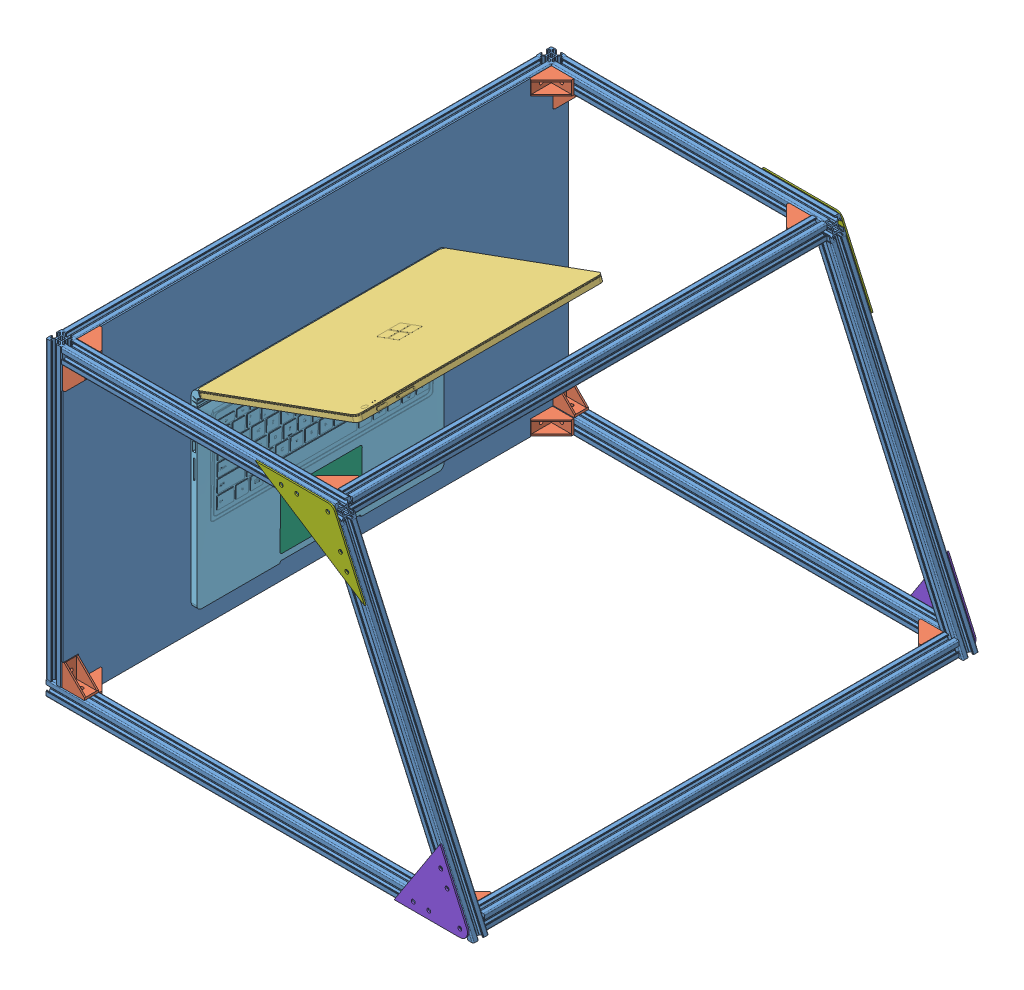
SolidWorks assembly LC, configuration Default. Lengths in mm.
Overall size (629.33 485.11 655).
26 component instances, 8 part files, 64 mates.
Components (placement in the parent):
- Laptop Area Chassis-1: Laptop Area Chassis [Default<As Machined>] at (20.6223 518.2446 805.6712) size (550.43 400 651)
- L- Bracket-1: L- Bracket [Default] at (21.1239 508.2457 184.6697) x (-1 0 0) z (0 1 0) size (18 29 29)
- L- Bracket-2: L- Bracket [Default] at (365.6239 517.7435 184.6697) x (0 -1 0) z (0 0 -1) size (18 29 29)
- L- Bracket-3: L- Bracket [Default] at (535.6239 138.7457 184.6697) x (0 1 0) z (1 0 0) size (18 29 29)
- L- Bracket-4: L- Bracket [Default] at (535.6239 138.7457 795.671) x (0 1 0) z (0 0 1) size (18 29 29)
- L- Bracket-5: L- Bracket [Default] at (365.6239 517.7435 795.671) x (0 1 0) z (0 0 1) size (18 29 29)
- L- Bracket-6: L- Bracket [Default] at (21.1239 508.2457 795.671) x (1 0 0) z (0 1 0) size (18 29 29)
- L- Bracket-7: L- Bracket [Default] at (21.1239 148.2435 795.671) size (18 29 29)
- L- Bracket-8: L- Bracket [Default] at (21.1234 148.2435 184.6697) x (-1 0 0) z (0 0 -1) size (18 29 29)
- L- Bracket-10: L- Bracket [Default] at (30.6226 518.7457 795.671) x (0 -1 0) z (0 0 1) size (18 29 29)
- L- Bracket-11: L- Bracket [Default] at (30.6212 508.2458 805.1697) x (0 0 1) z (0 1 0) size (18 29 29)
- L- Bracket-12: L- Bracket [Default] at (30.6212 148.2435 806.171) x (0 0 -1) z (0 -1 0) size (18 29 29)
- L- Bracket-13: L- Bracket [Default] at (30.6226 138.7457 795.671) x (0 -1 0) z (0 0 1) size (18 29 29)
- L- Bracket-14: L- Bracket [Default] at (30.6226 517.7435 184.6697) x (0 -1 0) z (-1 0 0) size (18 29 29)
- L- Bracket-15: L- Bracket [Default] at (30.6212 508.2458 174.1697) x (0 0 1) z (0 1 0) size (18 29 29)
- L- Bracket-16: L- Bracket [Default] at (30.6226 138.7457 184.6697) x (0 -1 0) z (-1 0 0) size (18 29 29)
- L- Bracket-17: L- Bracket [Default] at (30.6212 148.2435 175.171) x (0 0 -1) z (0 -1 0) size (18 29 29)
- Laptop-1: Laptop [Default] at (141.9009 439.4853 491.6697) x (0 0 -1) z (0.34202 -0.939693 0) size (328.58 310.16 232.04) (flexible)
  - Monitor-1: Monitor [Default] at origin size (318 220.5 8.05)
  - Display-1: Display [Default] at (0 0 7.5) size (326.85 238.53 0.46)
  - Main Body-1: Main Body [Default] at origin size (318.39 103.66 231.99)
  - Mouse Pad-1: Mouse Pad [Default] at (0 -91.311 -34.924) x (1 0 0) z (0 0.934014 0.357236) size (105 71 0.7)
- LC Lower Level-1: LC Lower Level [Default] at (97.0709 784.7388 817.6697) x (-0.543907 -0.839146 0) z (0.839146 -0.543907 0) size (52.47 2 167.83)
- LC Lower Level-2: LC Lower Level [Default] at (732.6289 372.7908 162.671) x (-0.543907 -0.839146 0) z (-0.839146 0.543907 0) size (52.47 2 167.83)
- LC Upper Level-1: LC Upper Level [Default] at (500.3977 162.4909 164.671) x (-0.839167 0.543874 0) z (-0.543874 -0.839167 0) size (75.53 2 108.78)
- LC Upper Level-2: LC Upper Level [Default] at (505.0206 169.6236 815.6697) x (-0.839167 0.543874 0) z (0.543874 0.839167 0) size (75.53 2 108.78)
Mates (geometry in assembly coordinates):
- Coincident3: coincident: plane of assembly; plane of assembly; plane of Laptop Area Chassis-1 through (375.6223 514.4957 184.6697) normal (0 0 1); plane of L- Bracket-2 through (336.6239 526.7435 184.6697) normal (0 0 -1)
- Coincident4: coincident: plane of assembly; plane of assembly; plane of Laptop Area Chassis-1 through (365.6239 521.9936 174.6712) normal (-1 0 0); plane of L- Bracket-2 through (365.6239 526.7435 184.6697) normal (1 0 0)
- Coincident5: coincident: line of assembly; line of assembly; line of Laptop Area Chassis-1 through (365.6239 526.7435 184.6697) axis (0 0 1); line of L- Bracket-2 through (365.6239 526.7435 184.6697) axis (0 0 1)
- Coincident6: coincident: plane of assembly; plane of assembly; plane of Laptop Area Chassis-1 through (375.6223 521.9936 795.671) normal (0 0 -1); plane of L- Bracket-5 through (336.6239 508.7435 795.671) normal (0 0 1)
- Coincident7: coincident: plane of assembly; plane of assembly; plane of Laptop Area Chassis-1 through (365.6239 521.9936 174.6712) normal (-1 0 0); plane of L- Bracket-5 through (365.6239 508.7435 795.671) normal (1 0 0)
- Coincident8: coincident: line of assembly; line of assembly; line of Laptop Area Chassis-1 through (365.6239 526.7435 184.6697) axis (0 0 1); line of L- Bracket-5 through (365.6239 526.7435 795.671) axis (0 0 -1)
- Coincident9: coincident: plane of assembly; plane of assembly; plane of Laptop Area Chassis-1 through (535.6239 129.7457 174.6712) normal (-1 0 0); plane of L- Bracket-3 through (535.6239 129.7457 213.6697) normal (1 0 0)
- Coincident10: coincident: plane of assembly; plane of assembly; plane of Laptop Area Chassis-1 through (20.6223 129.7457 184.6697) normal (0 0 1); plane of L- Bracket-3 through (535.6239 129.7457 184.6697) normal (0 0 -1)
- Coincident11: coincident: line of assembly; line of assembly; line of Laptop Area Chassis-1 through (535.6239 129.7457 184.6697) axis (0 0 1); line of L- Bracket-3 through (535.6239 129.7457 213.6697) axis (0 0 -1)
- Coincident12: coincident: plane of assembly; plane of assembly; plane of Laptop Area Chassis-1 through (20.6223 146.7435 795.671) normal (0 0 -1); plane of L- Bracket-4 through (506.6239 129.7457 795.671) normal (0 0 1)
- Coincident13: coincident: plane of assembly; plane of assembly; plane of Laptop Area Chassis-1 through (535.6239 129.7457 174.6712) normal (-1 0 0); plane of L- Bracket-4 through (535.6239 129.7457 795.671) normal (1 0 0)
- Coincident14: coincident: line of assembly; line of assembly; line of Laptop Area Chassis-1 through (10.6234 129.7457 795.671) axis (1 0 0); line of L- Bracket-4 through (506.6239 129.7457 795.671) axis (1 0 0)
- Coincident17: coincident: plane of assembly; plane of assembly; plane of Laptop Area Chassis-1 through (12.1239 148.2435 174.6712) normal (0 1 0); plane of L- Bracket-7 through (12.1239 148.2435 795.671) normal (0 -1 0)
- Coincident18: coincident: plane of assembly; plane of assembly; plane of Laptop Area Chassis-1 through (16.8734 518.2446 795.671) normal (0 0 -1); plane of L- Bracket-7 through (12.1239 177.2435 795.671) normal (0 0 1)
- Coincident19: coincident: line of assembly; line of assembly; line of Laptop Area Chassis-1 through (12.1239 148.2435 184.6697) axis (0 0 1); line of L- Bracket-7 through (12.1239 148.2435 795.671) axis (0 0 -1)
- Coincident20: coincident: plane of assembly; plane of assembly; plane of Laptop Area Chassis-1 through (12.1234 518.2446 184.6697) normal (0 0 1); plane of L- Bracket-8 through (30.1234 177.2435 184.6697) normal (0 0 -1)
- Coincident21: coincident: plane of assembly; plane of assembly; plane of Laptop Area Chassis-1 through (12.1239 148.2435 174.6712) normal (0 1 0); plane of L- Bracket-8 through (30.1234 148.2435 184.6697) normal (0 -1 0)
- Coincident22: coincident: line of assembly; line of assembly; line of Laptop Area Chassis-1 through (12.1234 528.2436 184.6697) axis (0 -1 0); line of L- Bracket-8 through (12.1234 177.2435 184.6697) axis (0 -1 0)
- Coincident23: coincident: plane of assembly; plane of assembly; plane of Laptop Area Chassis-1 through (12.1234 518.2446 184.6697) normal (0 0 1); plane of L- Bracket-1 through (30.1239 508.2457 184.6697) normal (0 0 -1)
- Coincident24: coincident: plane of assembly; plane of assembly; plane of Laptop Area Chassis-1 through (16.8734 508.2457 174.6712) normal (0 -1 0); plane of L- Bracket-1 through (30.1239 508.2457 213.6697) normal (0 1 0)
- Coincident25: coincident: line of assembly; line of assembly; line of Laptop Area Chassis-1 through (12.1239 508.2457 184.6697) axis (0 0 1); line of L- Bracket-1 through (12.1239 508.2457 213.6697) axis (0 0 -1)
- Coincident26: coincident: plane of assembly; plane of assembly; plane of Laptop Area Chassis-1 through (16.8734 518.2446 795.671) normal (0 0 -1); plane of L- Bracket-6 through (12.1239 508.2457 795.671) normal (0 0 1)
- Coincident27: coincident: plane of assembly; plane of assembly; plane of Laptop Area Chassis-1 through (16.8734 508.2457 174.6712) normal (0 -1 0); plane of L- Bracket-6 through (12.1239 508.2457 766.671) normal (0 1 0)
- Coincident28: coincident: line of assembly; line of assembly; line of Laptop Area Chassis-1 through (12.1239 508.2457 184.6697) axis (0 0 1); line of L- Bracket-6 through (12.1239 508.2457 766.671) axis (0 0 1)
- Coincident29: coincident: plane of assembly; plane of assembly; plane of Laptop Area Chassis-1 through (20.6223 148.2435 814.1697) normal (0 1 0); plane of L- Bracket-12 through (59.6212 148.2435 815.171) normal (0 -1 0)
- Coincident30: coincident: plane of assembly; plane of assembly; plane of Laptop Area Chassis-1 through (30.6212 518.2446 814.1697) normal (1 0 0); plane of L- Bracket-12 through (30.6212 148.2435 815.171) normal (-1 0 0)
- Coincident31: coincident: line of assembly; line of assembly; line of Laptop Area Chassis-1 through (10.6234 148.2435 797.171) axis (1 0 0); line of L- Bracket-12 through (59.6212 148.2435 797.171) axis (-1 0 0)
- Coincident32: coincident: plane of assembly; plane of assembly; plane of Laptop Area Chassis-1 through (30.6226 146.7435 174.6712) normal (1 0 0); plane of L- Bracket-13 through (30.6226 147.7457 795.671) normal (-1 0 0)
- Coincident33: coincident: plane of assembly; plane of assembly; plane of Laptop Area Chassis-1 through (20.6223 134.4957 795.671) normal (0 0 -1); plane of L- Bracket-13 through (59.6226 147.7457 795.671) normal (0 0 1)
- Coincident34: coincident: line of assembly; line of assembly; line of Laptop Area Chassis-1 through (10.6234 129.7457 795.671) axis (1 0 0); line of L- Bracket-13 through (59.6226 129.7457 795.671) axis (-1 0 0)
- Coincident35: coincident: plane of assembly; plane of assembly; plane of Laptop Area Chassis-1 through (30.6226 514.4957 174.6712) normal (1 0 0); plane of L- Bracket-10 through (30.6226 527.7457 795.671) normal (-1 0 0)
- Coincident36: coincident: plane of assembly; plane of assembly; plane of Laptop Area Chassis-1 through (375.6223 509.7458 795.671) normal (0 0 -1); plane of L- Bracket-10 through (59.6226 527.7457 795.671) normal (0 0 1)
- Coincident37: coincident: line of assembly; line of assembly; line of Laptop Area Chassis-1 through (30.6226 509.7457 184.6697) axis (0 0 1); line of L- Bracket-10 through (30.6226 509.7457 795.671) axis (0 0 -1)
- Coincident38: coincident: plane of assembly; plane of assembly; plane of Laptop Area Chassis-1 through (375.6223 508.2458 801.9223) normal (0 -1 0); plane of L- Bracket-11 through (59.6212 508.2458 796.1697) normal (0 1 0)
- Coincident39: coincident: plane of assembly; plane of assembly; plane of Laptop Area Chassis-1 through (30.6212 518.2446 814.1697) normal (1 0 0); plane of L- Bracket-11 through (30.6212 508.2458 796.1697) normal (-1 0 0)
- Coincident40: coincident: line of assembly; line of assembly; line of Laptop Area Chassis-1 through (30.6212 528.2436 814.1697) axis (0 -1 0); line of L- Bracket-11 through (30.6212 508.2458 814.1697) axis (0 -1 0)
- Coincident41: coincident: plane of assembly; plane of assembly; plane of Laptop Area Chassis-1 through (375.6223 508.2458 170.9223) normal (0 -1 0); plane of L- Bracket-15 through (59.6212 508.2458 165.1697) normal (0 1 0)
- Coincident42: coincident: plane of assembly; plane of assembly; plane of Laptop Area Chassis-1 through (30.6212 518.2446 170.9223) normal (1 0 0); plane of L- Bracket-15 through (30.6212 508.2458 165.1697) normal (-1 0 0)
- Coincident43: coincident: line of assembly; line of assembly; line of Laptop Area Chassis-1 through (391.0494 508.2458 183.1697) axis (-1 0 0); line of L- Bracket-15 through (59.6212 508.2458 183.1697) axis (-1 0 0)
- Coincident44: coincident: plane of assembly; plane of assembly; plane of Laptop Area Chassis-1 through (375.6223 514.4957 184.6697) normal (0 0 1); plane of L- Bracket-14 through (30.6226 526.7435 184.6697) normal (0 0 -1)
- Coincident45: coincident: plane of assembly; plane of assembly; plane of Laptop Area Chassis-1 through (30.6226 526.7435 174.6712) normal (1 0 0); plane of L- Bracket-14 through (30.6226 526.7435 213.6697) normal (-1 0 0)
- Coincident46: coincident: line of assembly; line of assembly; line of Laptop Area Chassis-1 through (30.6226 526.7435 184.6697) axis (0 0 1); line of L- Bracket-14 through (30.6226 526.7435 213.6697) axis (0 0 -1)
- Coincident47: coincident: plane of assembly; plane of assembly; plane of Laptop Area Chassis-1 through (20.6223 129.7457 184.6697) normal (0 0 1); plane of L- Bracket-16 through (30.6226 147.7457 184.6697) normal (0 0 -1)
- Coincident48: coincident: plane of assembly; plane of assembly; plane of Laptop Area Chassis-1 through (30.6226 134.4957 174.6712) normal (1 0 0); plane of L- Bracket-16 through (30.6226 147.7457 213.6697) normal (-1 0 0)
- Coincident49: coincident: line of assembly; line of assembly; line of Laptop Area Chassis-1 through (30.6226 129.7457 184.6697) axis (0 0 1); line of L- Bracket-16 through (30.6226 129.7457 213.6697) axis (0 0 -1)
- Coincident50: coincident: plane of assembly; plane of assembly; plane of Laptop Area Chassis-1 through (20.6223 148.2435 183.1697) normal (0 1 0); plane of L- Bracket-17 through (59.6212 148.2435 184.171) normal (0 -1 0)
- Coincident51: coincident: plane of assembly; plane of assembly; plane of Laptop Area Chassis-1 through (30.6212 518.2446 183.1697) normal (1 0 0); plane of L- Bracket-17 through (30.6212 148.2435 184.171) normal (-1 0 0)
- Coincident52: coincident: line of assembly; line of assembly; line of Laptop Area Chassis-1 through (10.6234 148.2435 166.171) axis (1 0 0); line of L- Bracket-17 through (59.6212 148.2435 166.171) axis (-1 0 0)
- Coincident53: coincident: plane of Laptop Area Chassis-1 through (32.6212 518.2446 805.6712) normal (1 0 0); plane of ? through (32.6212 393.4178 901.2909) normal (-1 0 0)
- Parallel1: parallel: line of Laptop Area Chassis-1 through (32.6212 128.2457 766.571) axis (0 0 -1); line of ? through (32.6212 155.9635 644.6697) axis (0 0 -1)
- Distance3: distance = 165 mm: line of ? through (32.6212 382.2394 650.6697) axis (0 -1 0); line of Laptop Area Chassis-1 through (32.6212 479.1458 815.6697) axis (0 -1 0)
- Distance4: distance = 27.7178 mm: line of ? through (32.6212 155.9635 644.6697) axis (0 0 -1); line of Laptop Area Chassis-1 through (32.6212 128.2457 766.571) axis (0 0 -1)
- Coincident73: coincident: plane of assembly; plane of assembly; plane of Laptop Area Chassis-1 through (553.3803 141.7153 815.6697) normal (0 0 1); plane of LC Lower Level-1 through (375.622 518.2436 815.6697) normal (0 0 -1)
- Coincident76: coincident: plane of assembly; plane of assembly; plane of Laptop Area Chassis-1 through (375.6223 528.2436 809.4201) normal (0 1 0); plane of LC Lower Level-1 through (375.622 528.2436 815.6697) normal (0 1 0)
- Lock2: lock: unknown of Laptop Area Chassis-1; unknown of LC Lower Level-1
- Coincident78: coincident: plane of assembly; plane of assembly; plane of Laptop Area Chassis-1 through (375.6223 521.9936 164.671) normal (0 0 -1); plane of LC Lower Level-2 through (375.622 518.2436 164.671) normal (0 0 1)
- Coincident79: coincident: plane of Laptop Area Chassis-1 through (375.6223 528.2436 166.171) normal (0 1 0); plane of LC Lower Level-2 through (282.1037 528.2436 164.671) normal (0 1 0)
- Lock3: lock: unknown of Laptop Area Chassis-1; unknown of LC Lower Level-2
- Coincident81: coincident: plane of assembly; plane of assembly; plane of Laptop Area Chassis-1 through (553.3803 141.7153 815.6697) normal (0 0 1); plane of LC Upper Level-2 through (545.6207 138.2457 815.6697) normal (0 0 -1)
- Coincident82: coincident: plane of assembly; plane of assembly; plane of Laptop Area Chassis-1 through (554.7495 142.3279 809.4201) normal (0.912818 0.408366 0); plane of LC Upper Level-2 through (554.7489 142.3293 817.6697) normal (0.912818 0.408366 0)
- Lock4: lock: unknown of Laptop Area Chassis-1; unknown of LC Upper Level-2
- Coincident84: coincident: plane of assembly; plane of assembly; plane of Laptop Area Chassis-1 through (20.6223 134.4957 164.671) normal (0 0 -1); plane of LC Upper Level-1 through (545.6206 138.2458 164.671) normal (0 0 1)
- Coincident85: coincident: plane of assembly; plane of assembly; plane of Laptop Area Chassis-1 through (554.7495 142.3279 166.171) normal (0.912818 0.408366 0); plane of LC Upper Level-1 through (520.2125 219.5282 162.671) normal (0.912818 0.408366 0)
- Lock5: lock: unknown of Laptop Area Chassis-1; unknown of LC Upper Level-1
